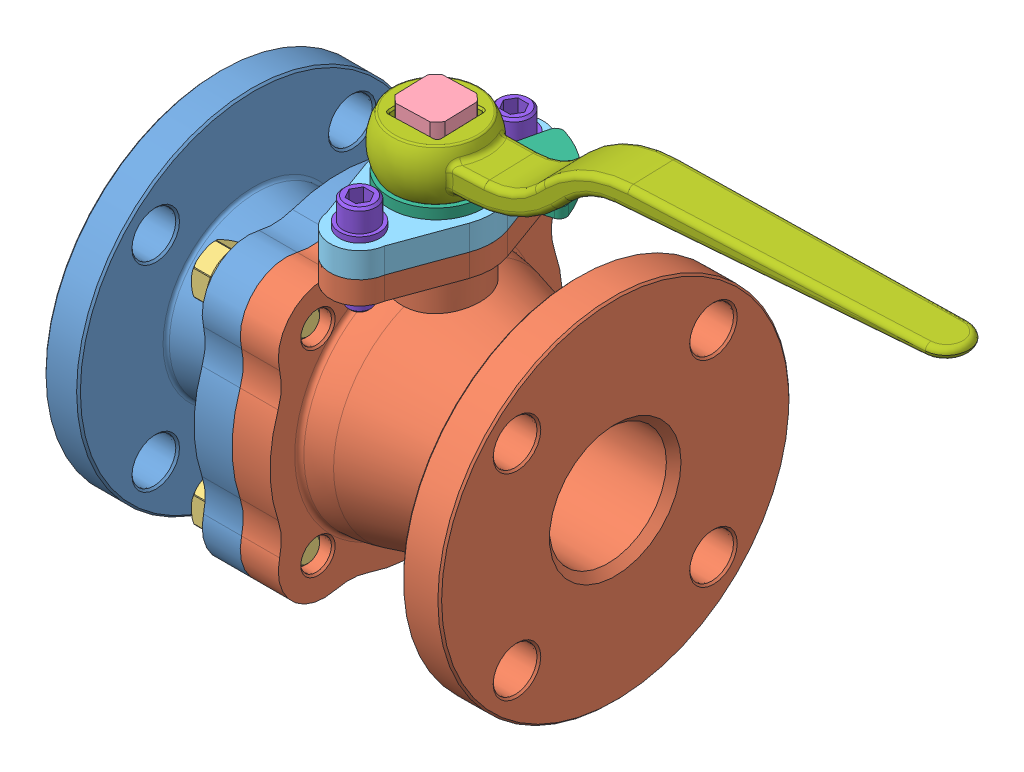
SolidWorks assembly Assem1, configuration Default. Lengths in mm.
Overall size (321.4 205.04 152.4).
12 component instances, 8 part files, 28 mates.
Components (placement in the parent):
- 1-OUTLET HOUSING-1: 1-OUTLET HOUSING [Default] at origin size (70.48 152.4 152.4)
- 2 - OUTLET HOUSING-1: 2 - OUTLET HOUSING [Default] at origin size (102.87 152.4 152.4)
- 7 - NUT BOLT-1: 7 - NUT BOLT [Default] at (82.5246 -42.7064 42.7064) x (0 1 0) z (0 0 1) size (24.51 41.75 24.51)
- 7 - NUT BOLT-6: 7 - NUT BOLT [Default] at (82.5246 42.7064 42.7064) x (0 1 0) z (0 0 1) size (24.51 41.75 24.51)
- 7 - NUT BOLT-7: 7 - NUT BOLT [Default] at (82.5246 42.7064 -42.7064) x (0 1 0) z (0 0 1) size (24.51 41.75 24.51)
- 7 - NUT BOLT-8: 7 - NUT BOLT [Default] at (82.5246 -42.7064 -42.7064) x (0 1 0) z (0 0 1) size (24.51 41.75 24.51)
- 4 - BALL VALVE-1: 4 - BALL VALVE [Default] at (95.6079 -25.4 0) x (0.031 0 0.999519) z (-0.999519 0 0.031) size (50.8 137.67 33.6)
- 3 - THERMO STATE FLANG-1: 3 - THERMO STATE FLANG [Default] at origin size (47.71 10.92 92.46)
- 5 - LOCK LEVER-1: 5 - LOCK LEVER [Default] at (95.4986 80.772 -0.1028) x (0.999519 0 -0.031) z (0.031 0 0.999519) size (62.42 4.45 62.42)
- 7 - HANDDLE-1: 7 - HANDDLE [Default] at (95.5666 101.9175 0.0439) x (0.999519 0 -0.031) z (0.031 0 0.999519) size (246.86 48.26 43.18)
- 6 - CAPS-2: 6 - CAPS [Default] at (95.885 51.4096 33.528) size (17.35 41.27 17.35)
- 6 - CAPS-3: 6 - CAPS [Default] at (95.885 51.4096 -33.528) size (17.35 41.27 17.35)
Mates (geometry in assembly coordinates):
- Coincident1: coincident aligned: plane of 1-OUTLET HOUSING-1 through (0 0 0) normal (0 0 1); plane of assembly through (0 0 0) normal (0 0 1)
- Coincident2: coincident aligned: plane of 1-OUTLET HOUSING-1 through (0 0 0) normal (0 1 0); plane of assembly through (0 0 0) normal (0 1 0)
- Coincident3: coincident aligned: plane of 1-OUTLET HOUSING-1 through (0 0 0) normal (1 0 0); plane of assembly through (0 0 0) normal (1 0 0)
- Coincident4: coincident anti-aligned: plane of 1-OUTLET HOUSING-1 through (70.485 -14.541 -42.0043) normal (1 0 0); plane of 2 - OUTLET HOUSING-1 through (70.485 14.541 -42.0043) normal (-1 0 0)
- Concentric1: concentric aligned: cylinder of 1-OUTLET HOUSING-1 through (70.485 42.7064 42.7064) axis (-1 0 0) radius 6.6675; cylinder of 2 - OUTLET HOUSING-1 through (86.995 42.7064 42.7064) axis (-1 0 0) radius 6.6675
- Concentric5: concentric aligned: cylinder of 1-OUTLET HOUSING-1 through (70.485 42.7064 -42.7064) axis (-1 0 0) radius 6.6675; cylinder of 2 - OUTLET HOUSING-1 through (86.995 42.7064 -42.7064) axis (-1 0 0) radius 6.6675
- Coincident6: coincident anti-aligned: plane of 1-OUTLET HOUSING-1 through (53.975 -14.541 -42.0043) normal (-1 0 0); plane of 7 - NUT BOLT-1 through (53.975 -36.3564 42.7064) normal (1 0 0)
- Concentric7: concentric aligned: cylinder of 1-OUTLET HOUSING-1 through (70.485 -42.7064 42.7064) axis (-1 0 0) radius 6.6675; cylinder of 7 - NUT BOLT-1 through (41.529 -42.7064 42.7064) axis (-1 0 0) radius 6.35
- Coincident9: coincident anti-aligned: plane of 1-OUTLET HOUSING-1 through (53.975 -14.541 -42.0043) normal (-1 0 0); plane of 7 - NUT BOLT-6 through (53.975 49.0564 42.7064) normal (1 0 0)
- Concentric8: concentric aligned: cylinder of 1-OUTLET HOUSING-1 through (70.485 42.7064 42.7064) axis (-1 0 0) radius 6.6675; cylinder of 7 - NUT BOLT-6 through (41.529 42.7064 42.7064) axis (-1 0 0) radius 6.35
- Coincident10: coincident anti-aligned: plane of 1-OUTLET HOUSING-1 through (53.975 -14.541 -42.0043) normal (-1 0 0); plane of 7 - NUT BOLT-7 through (53.975 49.0564 -42.7064) normal (1 0 0)
- Concentric9: concentric aligned: cylinder of 1-OUTLET HOUSING-1 through (70.485 42.7064 -42.7064) axis (-1 0 0) radius 6.6675; cylinder of 7 - NUT BOLT-7 through (41.529 42.7064 -42.7064) axis (-1 0 0) radius 6.35
- Coincident11: coincident anti-aligned: plane of 1-OUTLET HOUSING-1 through (53.975 -14.541 -42.0043) normal (-1 0 0); plane of 7 - NUT BOLT-8 through (53.975 -36.3564 -42.7064) normal (1 0 0)
- Concentric10: concentric aligned: cylinder of 1-OUTLET HOUSING-1 through (70.485 -42.7064 -42.7064) axis (-1 0 0) radius 6.6675; cylinder of 7 - NUT BOLT-8 through (41.529 -42.7064 -42.7064) axis (-1 0 0) radius 6.35
- Concentric11: concentric anti-aligned: cylinder of 2 - OUTLET HOUSING-1 through (95.6079 -76.201 0) axis (0 1 0) radius 12.7; cylinder of 4 - BALL VALVE-1 through (95.6079 -25.4 0) axis (0 -1 0) radius 12.7
- Tangent1: tangent aligned: cylinder of 2 - OUTLET HOUSING-1 through (86.995 0 0) axis (-1 0 0) radius 25.4; sphere of 4 - BALL VALVE-1
- Coincident12: coincident anti-aligned: plane of 2 - OUTLET HOUSING-1 through (0 69.85 0) normal (0 1 0); plane of 3 - THERMO STATE FLANG-1 through (95.6079 69.85 0) normal (0 -1 0)
- Concentric12: concentric aligned: cylinder of 4 - BALL VALVE-1 through (95.6079 -25.4 0) axis (0 -1 0) radius 12.7; cylinder of 3 - THERMO STATE FLANG-1 through (95.6079 80.772 0) axis (0 -1 0) radius 12.7
- Coincident13: coincident anti-aligned: plane of 3 - THERMO STATE FLANG-1 through (95.6079 80.772 0) normal (0 1 0); plane of 5 - LOCK LEVER-1 through (95.4986 80.772 -0.1028) normal (0 -1 0)
- Coincident14: coincident anti-aligned: plane of 4 - BALL VALVE-1 through (103.1669 81.28 10.2055) normal (0.031 0 0.999519); plane of 5 - LOCK LEVER-1 through (85.2894 85.217 10.7599) normal (-0.031 0 -0.999519)
- Coincident16: coincident anti-aligned: plane of 4 - BALL VALVE-1 through (105.8134 81.28 -7.559) normal (0.999519 0 -0.031); plane of 5 - LOCK LEVER-1 through (105.7077 85.217 -10.9655) normal (-0.999519 0 0.031)
- Coincident17: coincident anti-aligned: plane of 4 - BALL VALVE-1 through (105.8134 81.28 -7.559) normal (0.999519 0 -0.031); plane of 7 - HANDDLE-1 through (105.7143 85.217 -10.7533) normal (-0.999519 0 0.031)
- Coincident18: coincident anti-aligned: plane of 4 - BALL VALVE-1 through (88.0489 81.28 -10.2055) normal (-0.031 0 -0.999519); plane of 7 - HANDDLE-1 through (84.7694 85.217 -10.1038) normal (0.031 0 0.999519)
- Coincident19: coincident anti-aligned: plane of 5 - LOCK LEVER-1 through (95.4986 85.217 -0.1028) normal (0 1 0); plane of 7 - HANDDLE-1 through (76.3957 85.217 -20.9619) normal (0 -1 0)
- Coincident20: coincident anti-aligned: plane of 3 - THERMO STATE FLANG-1 through (95.6079 80.772 0) normal (0 1 0); plane of 6 - CAPS-2 through (104.5591 80.772 33.528) normal (0 -1 0)
- Concentric13: concentric aligned: cylinder of 3 - THERMO STATE FLANG-1 through (95.885 80.772 33.528) axis (0 -1 0) radius 4.826; cylinder of 6 - CAPS-2 through (95.885 51.4096 33.528) axis (0 -1 0) radius 4.7625
- Coincident22: coincident anti-aligned: plane of 3 - THERMO STATE FLANG-1 through (95.6079 80.772 0) normal (0 1 0); plane of 6 - CAPS-3 through (104.5591 80.772 -33.528) normal (0 -1 0)
- Concentric14: concentric aligned: cylinder of 3 - THERMO STATE FLANG-1 through (95.885 80.772 -33.528) axis (0 -1 0) radius 4.826; cylinder of 6 - CAPS-3 through (95.885 51.4096 -33.528) axis (0 -1 0) radius 4.7625
